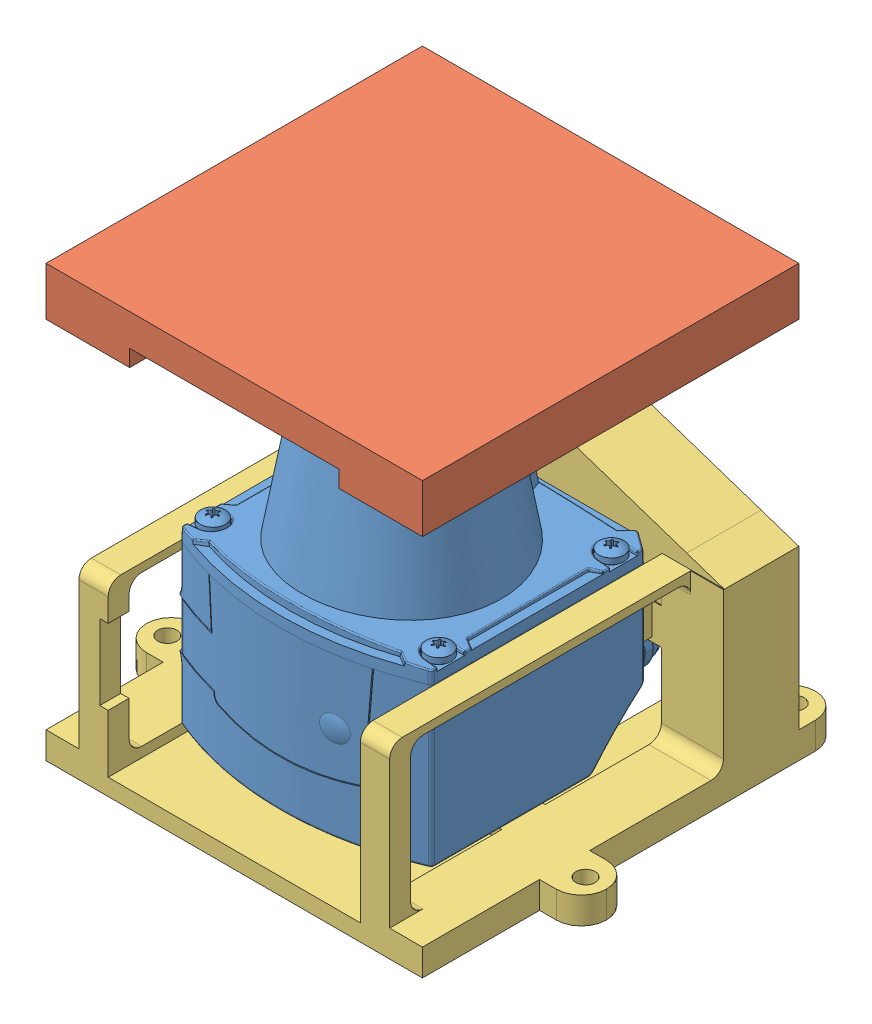
SolidWorks assembly Assemblage Support SICK TIM561, configuration Défaut. Lengths in mm.
Overall size (110 103 100).
3 component instances, 3 part files, 9 mates.
Components (placement in the parent):
- TIM561-Part-1: TIM561-Part [Default] at (-5.6593 -8.7053 119.95) x (0 0 1) z (-1 0 0) size (76.29 86.12 61.14)
- Support Sick TIM562 Haut-1: Support Sick TIM562 Haut [Défaut] at (-5.6093 -36.3032 115) size (90 39 90)
- Support Sick TIM562 Bas-1: Support Sick TIM562 Bas [Défaut] at (-5.6093 -36.3032 115) size (110 79 100)
Mates (geometry in assembly coordinates):
- Coaxiale1: concentric anti-aligned: cylinder of Support Sick TIM561 MK1 B_M-1 through (19.8407 -7.8632 59.999) axis (0 0 1) radius 1.75; cylinder of TIM561-Part-1 through (19.8407 -7.8632 90.45) axis (0 0 -1) radius 1.25
- Parallèle1: parallel anti-aligned: cylinder of Support Sick TIM561 MK1 B_M-1 through (-31.1593 -36.3042 121) axis (0 1 0) radius 1.75; cylinder of TIM561-Part-1 through (-31.1623 -29.7611 120.95) axis (0 -1 0) radius 1.25
- Coïncidente1: coincident anti-aligned: plane of Support Sick TIM561 MK1 B_M-1 through (-5.7093 -36.3032 90.45) normal (0 0 1); plane of TIM561-Part-1 through (-30.7665 -7.8693 90.45) normal (0 0 -1)
- Coaxiale2: concentric anti-aligned: cylinder of TIM561-Part-1 through (-31.1593 -7.8632 90.45) axis (0 0 -1) radius 1.25; cylinder of Support Sick TIM562 Bas-1 through (-31.1593 -7.8632 59.999) axis (0 0 1) radius 1.75
- Parallèle2: parallel anti-aligned: cylinder of TIM561-Part-1 through (19.8407 -7.8632 90.45) axis (0 0 -1) radius 1.25; cylinder of Support Sick TIM562 Bas-1 through (19.9407 -7.8632 59.999) axis (0 0 1) radius 1.75
- Coïncidente2: coincident anti-aligned: plane of TIM561-Part-1 through (-30.7665 -7.8693 90.45) normal (0 0 -1); plane of Support Sick TIM562 Bas-1 through (-5.6093 -36.3032 90.45) normal (0 0 1)
- Coïncidente9: coincident anti-aligned: plane of Support Sick TIM562 Haut-1 through (-5.6093 42.6968 115) normal (0 -1 0); plane of Support Sick TIM562 Bas-1 through (-5.6093 42.6968 115) normal (0 1 0)
- Coïncidente10: coincident aligned: plane of Support Sick TIM562 Haut-1 through (-50.6093 -32.3032 70) normal (0 0 -1); plane of Support Sick TIM562 Bas-1 through (-50.6093 -32.3032 70) normal (0 0 -1)
- Coïncidente11: coincident aligned: plane of Support Sick TIM562 Haut-1 through (-13.1093 55.0968 70) normal (-1 0 0); plane of Support Sick TIM562 Bas-1 through (-13.1093 55.0968 70) normal (-1 0 0)
